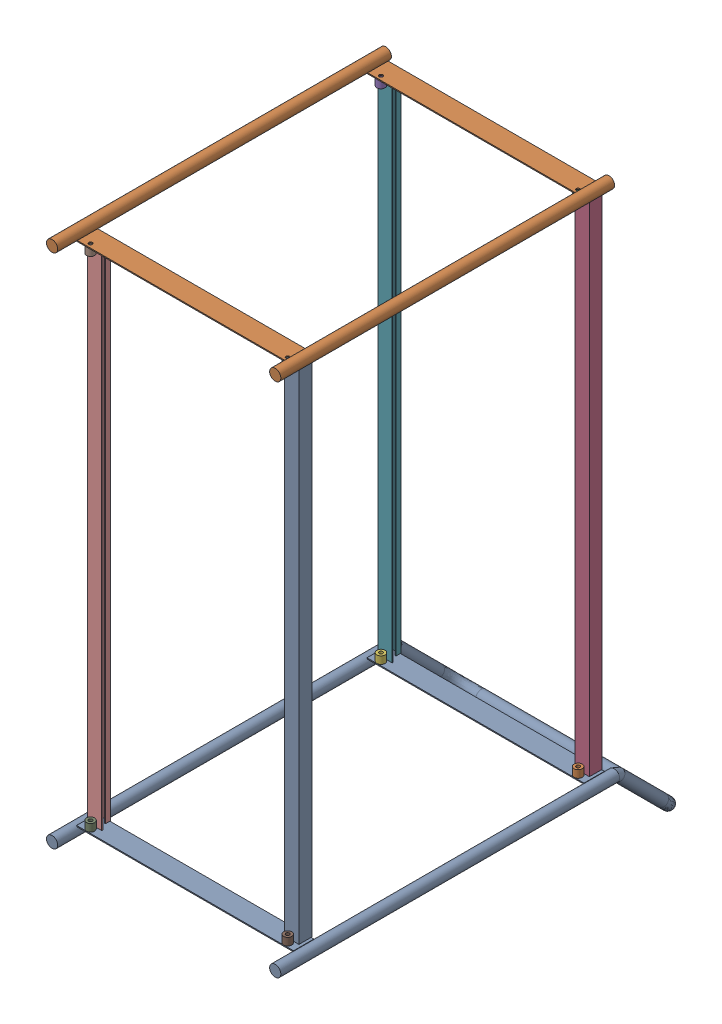
SolidWorks assembly chario, configuration Default. Lengths in mm.
Overall size (462.59 1160.72 806.28).
6 component instances, 3 part files, 15 mates.
Components (placement in the parent):
- grand_cote-1: grand_cote [Default] at (-186.8276 71.6485 -150.3104) size (462.59 147.72 806.28)
- fente-1: fente [Default] at (-7.3276 1074.6485 -123.3104) x (-1 0 0) z (0 -1 0) size (28 41.2 993)
- fente-2: fente [Default] at (-366.3276 81.6485 -123.3104) x (1 0 0) z (0 1 0) size (28 41.2 993)
- fente-3: fente [Default] at (-366.3276 81.6485 446.6896) x (1 0 0) z (0 1 0) size (28 41.2 993)
- fente-4: fente [Default] at (-7.3276 1074.6485 446.6896) x (-1 0 0) z (0 -1 0) size (28 41.2 993)
- petit_cote-1: petit_cote [Default] at (-186.8276 1084.6485 -150.3104) x (-1 0 0) z (0 0 1) size (460 22 655)
Mates (geometry in assembly coordinates):
- Concentric1: concentric anti-aligned: cylinder of grand_cote-1 through (6.6724 -65.0742 -115.3104) axis (0 1 0) radius 3.5; cylinder of fente-1 through (6.6724 96.2485 -115.3104) axis (0 -1 0) radius 3.5
- Coincident1: coincident anti-aligned: plane of grand_cote-1 through (-186.8276 81.6485 -150.3104) normal (0 1 0); plane of fente-1 through (-7.3276 81.6485 -123.3104) normal (0 -1 0)
- Parallel1: parallel aligned: plane of grand_cote-1 through (-399.8276 81.6485 -147.3104) normal (0 0 -1); plane of fente-1 through (20.6724 81.6485 -148.5104) normal (0 0 -1)
- Concentric2: concentric anti-aligned: cylinder of grand_cote-1 through (-380.3276 -65.0742 -115.3104) axis (0 1 0) radius 3.5; cylinder of fente-2 through (-380.3276 96.2485 -115.3104) axis (0 -1 0) radius 3.5
- Coincident3: coincident anti-aligned: plane of grand_cote-1 through (-186.8276 81.6485 -150.3104) normal (0 1 0); plane of fente-2 through (-366.3276 81.6485 -123.3104) normal (0 -1 0)
- Parallel2: parallel aligned: plane of grand_cote-1 through (-399.8276 81.6485 -147.3104) normal (0 0 -1); plane of fente-2 through (-394.3276 1074.6485 -148.5104) normal (0 0 -1)
- Concentric3: concentric anti-aligned: cylinder of grand_cote-1 through (-380.3276 -65.0742 454.6896) axis (0 1 0) radius 3.5; cylinder of fente-3 through (-380.3276 96.2485 454.6896) axis (0 -1 0) radius 3.5
- Coincident5: coincident anti-aligned: plane of grand_cote-1 through (-186.8276 81.6485 419.6896) normal (0 1 0); plane of fente-3 through (-366.3276 81.6485 446.6896) normal (0 -1 0)
- Parallel3: parallel aligned: plane of grand_cote-1 through (-399.8276 81.6485 422.6896) normal (0 0 -1); plane of fente-3 through (-394.3276 1074.6485 421.4896) normal (0 0 -1)
- Concentric4: concentric anti-aligned: cylinder of grand_cote-1 through (6.6724 -65.0742 454.6896) axis (0 1 0) radius 3.5; cylinder of fente-4 through (6.6724 96.2485 454.6896) axis (0 -1 0) radius 3.5
- Coincident7: coincident anti-aligned: plane of grand_cote-1 through (-186.8276 81.6485 419.6896) normal (0 1 0); plane of fente-4 through (-7.3276 81.6485 446.6896) normal (0 -1 0)
- Parallel4: parallel aligned: plane of grand_cote-1 through (-399.8276 81.6485 422.6896) normal (0 0 -1); plane of fente-4 through (20.6724 81.6485 421.4896) normal (0 0 -1)
- Concentric5: concentric anti-aligned: cylinder of fente-2 through (-380.3276 1060.0485 -115.3104) axis (0 1 0) radius 3.5; cylinder of petit_cote-1 through (-380.3276 1095.6485 -115.3104) axis (0 -1 0) radius 3.5
- Coincident9: coincident anti-aligned: plane of fente-2 through (-366.3276 1074.6485 -123.3104) normal (0 1 0); plane of petit_cote-1 through (-186.8276 1074.6485 -150.3104) normal (0 -1 0)
- Parallel5: parallel aligned: plane of fente-2 through (-394.3276 1074.6485 -148.5104) normal (0 0 -1); plane of petit_cote-1 through (26.1724 1074.6485 -147.3104) normal (0 0 -1)
